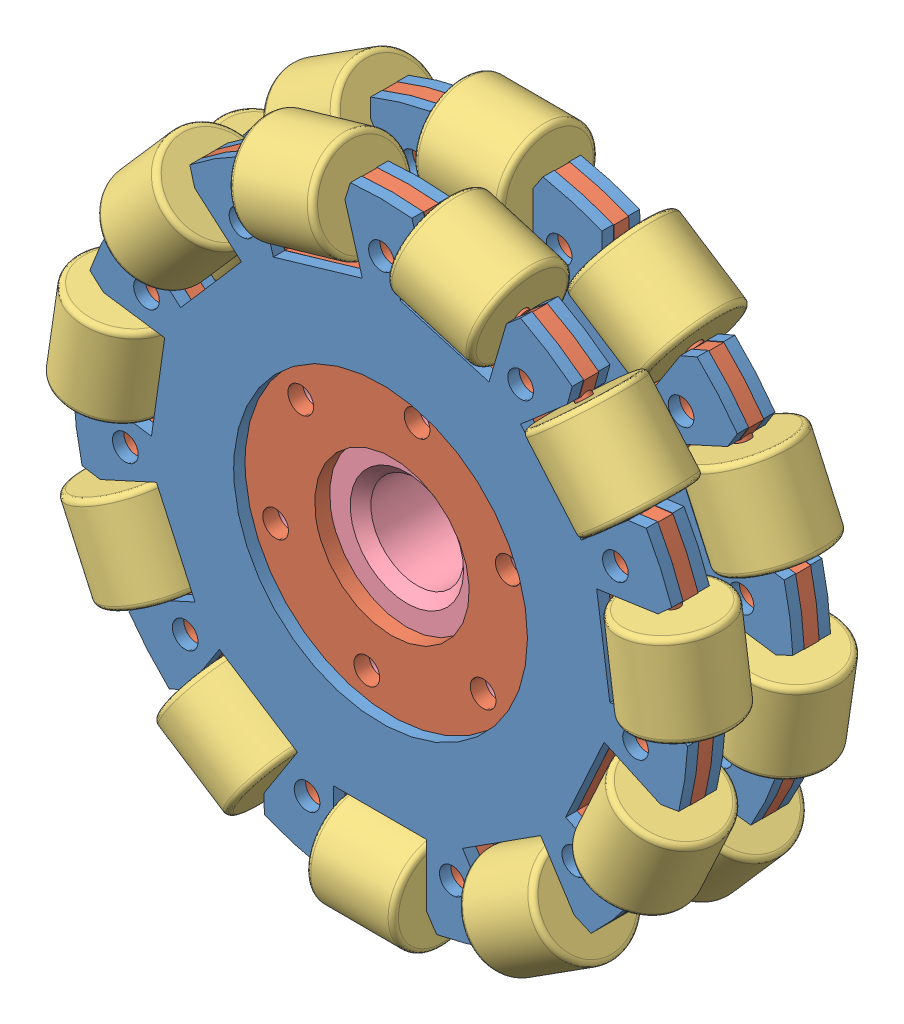
SolidWorks assembly omni wheel 127mm, configuration 預設. Lengths in mm.
Overall size (147.63 147.7 47.17).
31 component instances, 4 part files, 9 mates.
Components (placement in the parent):
- omni wheel 127mm 1-1: omni wheel 127mm 1 [預設] at origin size (147.34 146.72 26.77)
  - Part1-1: Part1 [Default] at (0 0 5.11) size (119.14 118.25 2.21)
  - Part3-1: Part3 [Default] at (0 0 2.21) x (0.960473 0.278374 0) z (0 0 1) size (119.14 118.23 2.9)
  - Part1-2: Part1 [Default] at origin size (119.14 118.25 2.21)
  - Part4-1: Part4 [Default] at (-22.2066 50.6262 3.66) x (0.34688 -0.54389 0.764106) z (-0.843122 -0.537723 0) size (19 19 17)
  - Part4-2: Part4 [Default] at (-46.0519 30.5837 3.66) x (0.585863 -0.270012 0.764106) z (-0.418564 -0.908187 0) size (19 19 17)
  - Part4-3: Part4 [Default] at (-55.2761 0.8311 3.66) x (0.638839 0.089593 0.764106) z (0.138884 -0.990309 0) size (19 19 17)
  - Part4-4: Part4 [Default] at (-46.9505 -29.1854 3.66) x (0.488988 0.420753 0.764106) z (0.652238 -0.758014 0) size (19 19 17)
  - Part4-5: Part4 [Default] at (-23.7185 -49.9357 3.66) x (0.183887 0.618327 0.764106) z (0.958511 -0.285056 0) size (19 19 17)
  - Part4-6: Part4 [Default] at (7.044 -54.8318 3.66) x (-0.179597 0.619586 0.764106) z (0.960463 0.278406 0) size (19 19 17)
  - Part4-7: Part4 [Default] at (35.5701 -42.3191 3.66) x (-0.48606 0.424131 0.764106) z (0.657476 0.753476 0) size (19 19 17)
  - Part4-8: Part4 [Default] at (52.8029 -16.3705 3.66) x (-0.638203 0.094018 0.764106) z (0.145744 0.989322 0) size (19 19 17)
  - Part4-9: Part4 [Default] at (53.2712 14.7757 3.66) x (-0.58772 -0.265946 0.764106) z (-0.412261 0.911066 0) size (19 19 17)
  - Part4-10: Part4 [Default] at (36.8262 41.2307 3.66) x (-0.350641 -0.541473 0.764106) z (-0.839375 0.543553 0) size (19 19 17)
  - Part4-11: Part4 [Default] at (8.6892 54.5952 3.66) x (-0.002235 -0.645087 0.764106) z (-0.999994 0.003465 0) size (19 19 17)
- Part5-1: Part5 [Default] at (0 0 5.11) x (0.978669 -0.205441 0) z (0 0 1) size (57 57 17.5)
- omni wheel 127mm 1-2: omni wheel 127mm 1 [預設] at (0 0 20.4) x (-1 0 0) z (0 0 1) size (147.34 146.72 26.77)
  - Part1-1: Part1 [Default] at (0 0 5.11) size (119.14 118.25 2.21)
  - Part3-1: Part3 [Default] at (0 0 2.21) x (0.960473 0.278374 0) z (0 0 1) size (119.14 118.23 2.9)
  - Part1-2: Part1 [Default] at origin size (119.14 118.25 2.21)
  - Part4-1: Part4 [Default] at (-22.2066 50.6262 3.66) x (0.34688 -0.54389 0.764106) z (-0.843122 -0.537723 0) size (19 19 17)
  - Part4-2: Part4 [Default] at (-46.0519 30.5837 3.66) x (0.585863 -0.270012 0.764106) z (-0.418564 -0.908187 0) size (19 19 17)
  - Part4-3: Part4 [Default] at (-55.2761 0.8311 3.66) x (0.638839 0.089593 0.764106) z (0.138884 -0.990309 0) size (19 19 17)
  - Part4-4: Part4 [Default] at (-46.9505 -29.1854 3.66) x (0.488988 0.420753 0.764106) z (0.652238 -0.758014 0) size (19 19 17)
  - Part4-5: Part4 [Default] at (-23.7185 -49.9357 3.66) x (0.183887 0.618327 0.764106) z (0.958511 -0.285056 0) size (19 19 17)
  - Part4-6: Part4 [Default] at (7.044 -54.8318 3.66) x (-0.179597 0.619586 0.764106) z (0.960463 0.278406 0) size (19 19 17)
  - Part4-7: Part4 [Default] at (35.5701 -42.3191 3.66) x (-0.48606 0.424131 0.764106) z (0.657476 0.753476 0) size (19 19 17)
  - Part4-8: Part4 [Default] at (52.8029 -16.3705 3.66) x (-0.638203 0.094018 0.764106) z (0.145744 0.989322 0) size (19 19 17)
  - Part4-9: Part4 [Default] at (53.2712 14.7757 3.66) x (-0.58772 -0.265946 0.764106) z (-0.412261 0.911066 0) size (19 19 17)
  - Part4-10: Part4 [Default] at (36.8262 41.2307 3.66) x (-0.350641 -0.541473 0.764106) z (-0.839375 0.543553 0) size (19 19 17)
  - Part4-11: Part4 [Default] at (8.6892 54.5952 3.66) x (-0.002235 -0.645087 0.764106) z (-0.999994 0.003465 0) size (19 19 17)
Mates (geometry in assembly coordinates):
- 重合/共線/共點1: coincident anti-aligned: plane of omni wheel 127mm 1-1/Part3-1 through (11.3871 0 5.11) normal (0 0 1); plane of Part5-1 through (11.3871 0 5.11) normal (0 0 -1)
- 同軸心1: concentric aligned: circle of omni wheel 127mm 1-1/Part3-1; circle of Part5-1
- 同軸心2: concentric aligned: circle of omni wheel 127mm 1-1/Part3-1; circle of Part5-1
- 重合/共線/共點2: coincident anti-aligned: plane of Part5-1 through (11.3871 0 22.61) normal (0 0 1); plane of omni wheel 127mm 1-2/Part3-1 through (11.3871 0 22.61) normal (0 0 -1)
- 同軸心3: concentric anti-aligned: circle of Part5-1; circle of omni wheel 127mm 1-2/Part3-1
- 同軸心5: concentric aligned: circle of Part5-1; circle of omni wheel 127mm 1-2/Part3-1
- 重合/共線/共點3: coincident aligned: plane of omni wheel 127mm 1-1 through (11.3871 0 0) normal (0 0 1)
- 重合/共線/共點4: coincident aligned: plane of omni wheel 127mm 1-1 through (11.3871 0 0) normal (0 1 0)
- 重合/共線/共點5: coincident aligned: plane of omni wheel 127mm 1-1 through (0 0 0) normal (1 0 0)
